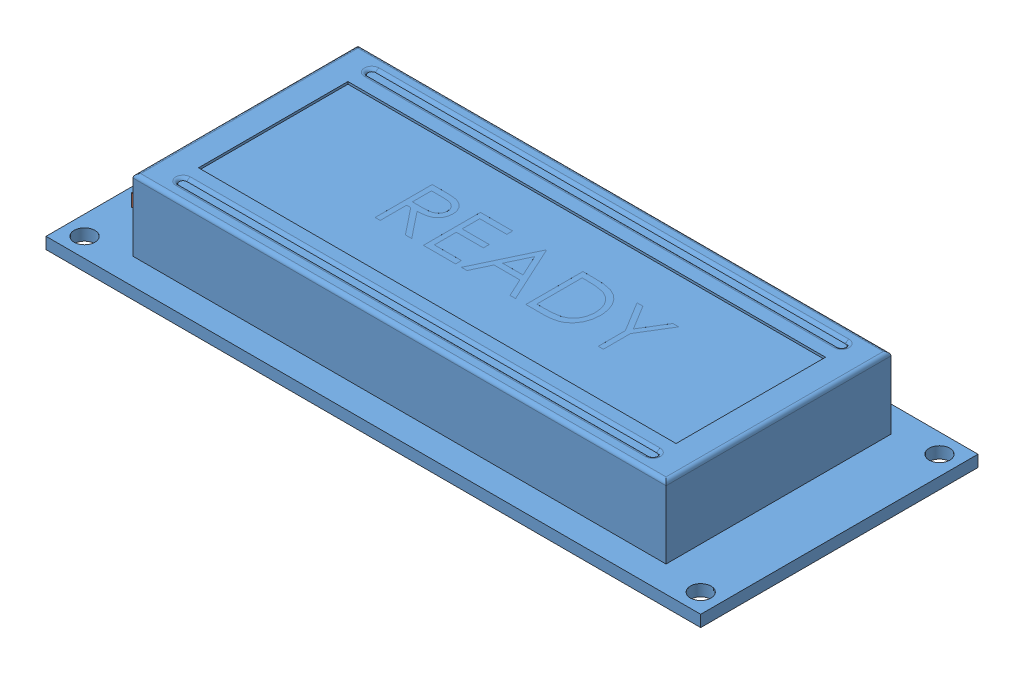
SolidWorks assembly MELT MT-16S2Dv7 assy, configuration По умолчанию. Lengths in mm.
Overall size (85 19.39 36).
3 component instances, 2 part files, 5 mates.
Components (placement in the parent):
- MELT MT-16S2Dv7-1: MELT MT-16S2Dv7 [Default] at (-1.7092 -7.5569 0) size (85 10.8 36)
- Pin header - 8 pin-1: Pin header - 8 pin [По умолчанию] at (-40.3722 -7.75 -5.0952) x (1 0 0) z (0 -1 0) size (5.08 10.16 11.5)
- Pin header - 8 pin-2: Pin header - 8 pin [По умолчанию] at (-40.3722 -7.5569 5.0648) x (1 0 0) z (0 -1 0) size (5.08 10.16 11.5)
Mates (geometry in assembly coordinates):
- Совпадение1: coincident anti-aligned: plane of Pin header - 8 pin-1 through (-40.3722 -10.15 -0.0152) normal (0 0 1); plane of Pin header - 8 pin-2 through (-40.3722 -9.9569 -0.0152) normal (0 0 -1)
- Совпадение2: coincident aligned: plane of Pin header - 8 pin-1 through (-42.9122 -10.15 -14.072) normal (-1 0 0); plane of Pin header - 8 pin-2 through (-42.9122 -9.9569 -3.912) normal (-1 0 0)
- Совпадение3: coincident anti-aligned: plane of MELT MT-16S2Dv7-1 through (-44.2092 -7.5569 18) normal (0 -1 0); plane of Pin header - 8 pin-2 through (-40.3722 -7.5569 -3.912) normal (0 1 0)
- Расстояние1: distance = 1.297 mm aligned: plane of Pin header - 8 pin-1 through (-42.9122 -10.15 -14.072) normal (-1 0 0); plane of MELT MT-16S2Dv7-1 through (-44.2092 -6.0569 -18) normal (-1 0 0)
- Расстояние2: distance = 7.8552 mm aligned: plane of Pin header - 8 pin-2 through (-40.3722 -9.9569 10.1448) normal (0 0 1); plane of MELT MT-16S2Dv7-1 through (40.7908 -6.0569 18) normal (0 0 1)
